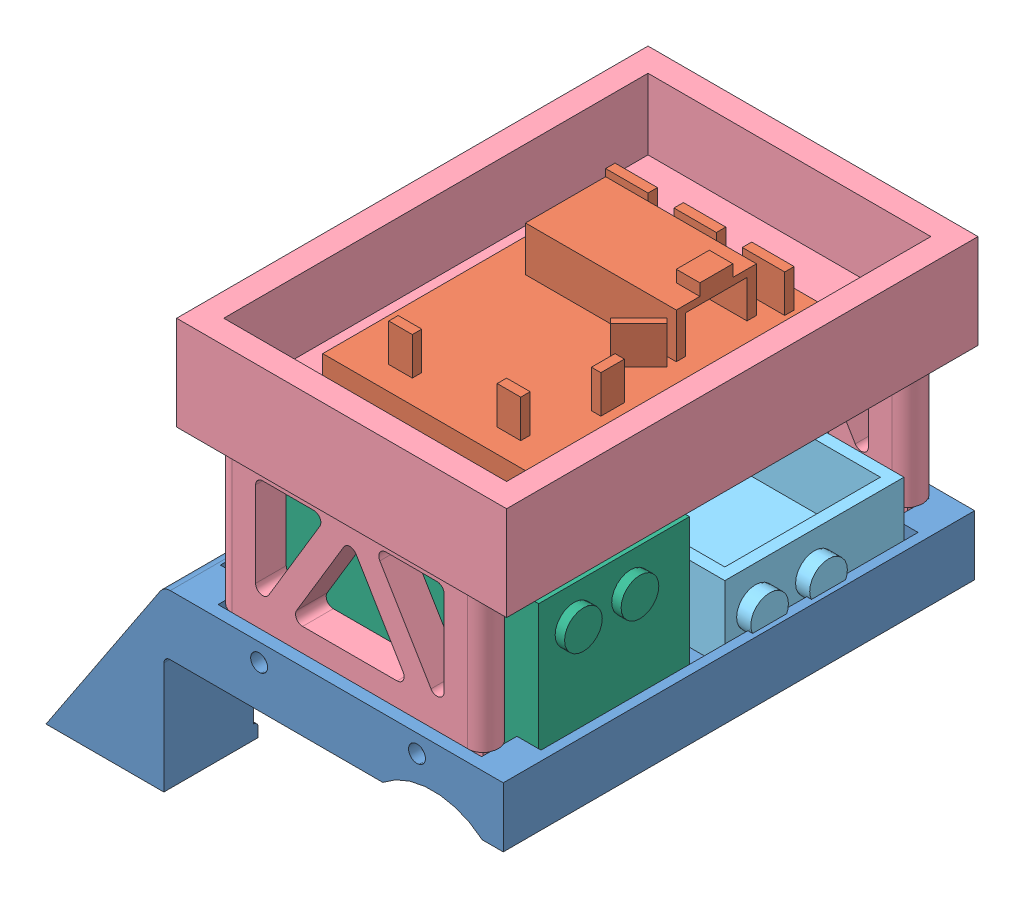
SolidWorks assembly Full Bot Rev 2, configuration Default. Lengths in mm.
Overall size (97 91.65 100.76).
6 component instances, 6 part files, 14 mates.
Components (placement in the parent):
- Plow Rev 2-1: Plow Rev 2 [Default] at origin size (97 37.7 100)
- Protoboard-1: Protoboard [Default] at (-6.2493 34.95 -19.5673) x (0 0 -1) z (1 0 0) size (62 17 46)
- Caster Wheel-1: Caster Wheel [Default] at (-43.5187 -33.35 -23.1783) x (0 0 1) z (-1 0 0) size (18.73 13 14.73)
- Battery Holder-1: Battery Holder [Default] at (28.852 -7.55 -45.3881) size (70 57.5 100)
- AAA batt holder-1: AAA batt holder [Default] at (-31.4822 -6.35 -24.1783) x (0 0 -1) z (1 0 0) size (38 16 67)
- AA batt holder-2: AA batt holder [Default] at (-31.9822 -6.35 15.8217) x (0 0 -1) z (1 0 0) size (32 32 67)
Mates (geometry in assembly coordinates):
- Concentric4: concentric: cylinder of Plow Rev 2-1 through (-43.5187 -26.7 -30.5443) axis (0 -1 0) radius 1.786; circle of Caster Wheel-1
- Concentric7: concentric: cylinder of Plow Rev 2-1 through (-43.5187 -26.7 -15.8123) axis (0 -1 0) radius 1.786; cylinder of Caster Wheel-1 through (-43.5187 -57.0925 -15.8123) axis (0 -1 0) radius 1
- Concentric8: concentric aligned: cylinder of Plow Rev 2-1 through (18.2178 -3.8 -78.2695) axis (0 0 1) radius 1.8; cylinder of Battery Holder-1 through (18.2178 -3.8 -75.7769) axis (0 0 1) radius 1.8
- Concentric9: concentric aligned: cylinder of Plow Rev 2-1 through (-15.2822 -3.8 -78.2695) axis (0 0 1) radius 1.8; cylinder of Battery Holder-1 through (-15.2822 -3.8 -75.7769) axis (0 0 1) radius 1.8
- Coincident1: coincident anti-aligned: plane of Protoboard-1 through (-6.2493 34.95 -19.5673) normal (0 -1 0); plane of Battery Holder-1 through (28.852 34.95 -45.3881) normal (0 1 0)
- Coincident2: coincident anti-aligned: plane of Protoboard-1 through (-6.2493 34.95 -19.5673) normal (0 -1 0); plane of Battery Holder-1 through (28.852 34.95 -45.3881) normal (0 1 0)
- Width1: width anti-aligned: plane of Protoboard-1 through (-21.5322 39.95 7.0643) normal (0 0 1); plane of Protoboard-1 through (-21.5322 39.95 -54.9357) normal (0 0 -1); plane of Battery Holder-1 through (-28.5322 34.95 21.0643) normal (0 0 -1); plane of Battery Holder-1 through (-28.5322 34.95 -68.9357) normal (0 0 1)
- Width2: width anti-aligned: plane of Battery Holder-1 through (31.4678 34.95 -68.9357) normal (-1 0 0); plane of Battery Holder-1 through (-28.5322 34.95 -68.9357) normal (1 0 0); plane of Protoboard-1 through (24.4678 39.95 7.0643) normal (1 0 0); plane of Protoboard-1 through (-21.5322 39.95 7.0643) normal (-1 0 0)
- Coincident4: coincident anti-aligned: plane of Plow Rev 2-1 through (0 -6.35 0) normal (0 1 0); plane of AAA batt holder-1 through (-31.4822 -6.35 -24.1783) normal (0 -1 0)
- Distance1: distance = 1 mm anti-aligned: plane of AAA batt holder-1 through (-31.4822 9.65 -62.1783) normal (0 0 -1); plane of Plow Rev 2-1 through (-33.4822 -6.35 -63.1783) normal (0 0 1)
- Width6: width anti-aligned: plane of AA batt holder-2 through (33.0178 25.65 15.8217) normal (1 0 0); plane of AA batt holder-2 through (-31.9822 25.65 15.8217) normal (-1 0 0); plane of Plow Rev 2-1 through (34.5178 -6.35 -63.1783) normal (-1 0 0); plane of Plow Rev 2-1 through (-33.4822 -6.35 -63.1783) normal (1 0 0)
- Coincident5: coincident anti-aligned: plane of Plow Rev 2-1 through (0 -6.35 0) normal (0 1 0); plane of AA batt holder-2 through (-31.9822 -6.35 15.8217) normal (0 -1 0)
- Distance2: distance = 1 mm anti-aligned: plane of Plow Rev 2-1 through (-33.4822 -6.35 16.8217) normal (0 0 -1); plane of AA batt holder-2 through (-31.9822 25.65 15.8217) normal (0 0 1)
- Coincident7: coincident anti-aligned: plane of Plow Rev 2-1 through (0 -26.7 0) normal (0 -1 0); plane of Caster Wheel-1 through (-39.2075 -26.7 -29.6628) normal (0 1 0)
